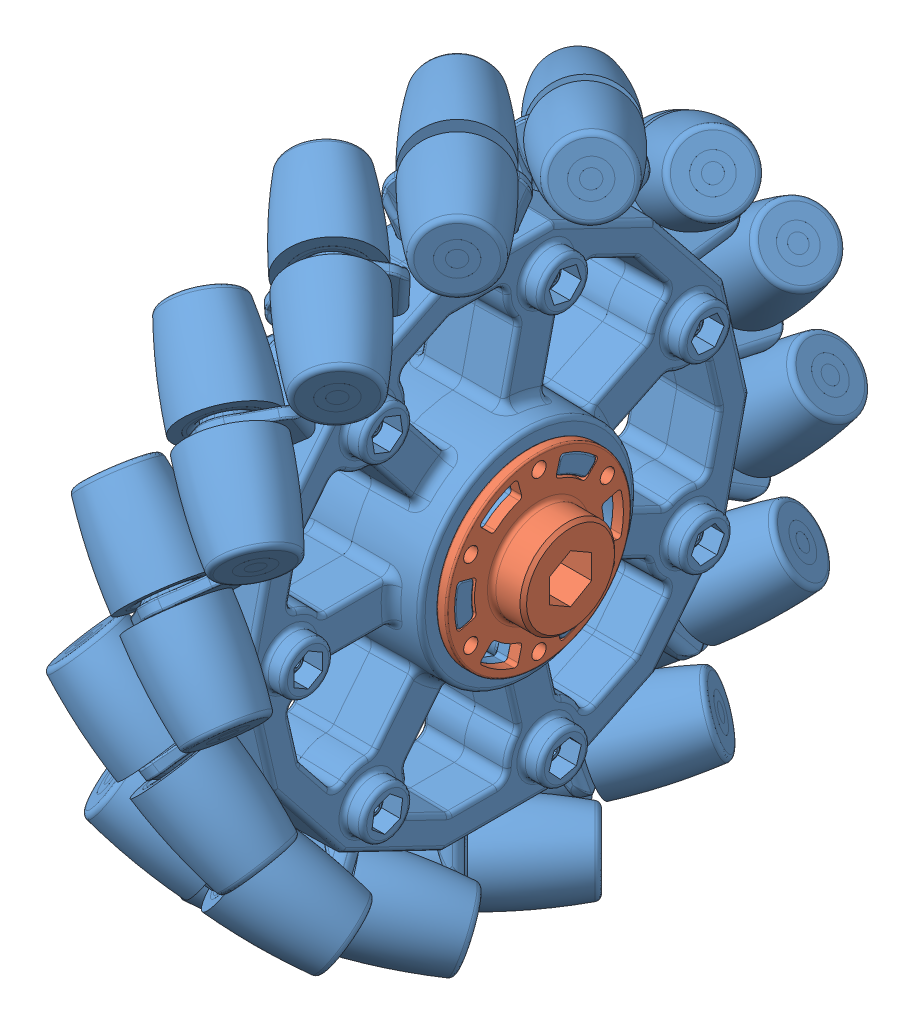
SolidWorks assembly 2018-202-A-Left, configuration Default. Lengths in mm.
Overall size (68.58 227.4 227.65).
3 component instances, 2 part files, 9 mates.
Components (placement in the parent):
- 2018-200-D017-Left-1: 2018-200-D017-Left [Default] x (0 -1 0) z (0 0 1) size (227.4 62.68 227.65)
- 2018-200-D005-1: 2018-200-D005 [Default] at (34.2942 0.0396 -0.0405) x (-1 0 0) z (0 -0.866025 -0.5) size (12.7 55.88 55.88)
- 2018-200-D005-2: 2018-200-D005 [Default] at (-34.2858 0.0396 -0.0405) size (12.7 55.88 55.88)
Mates (geometry in assembly coordinates):
- Coincident1: coincident: plane of 2018-200-D017-Left-1 through (0 0 0) normal (0 -1 0); plane of assembly
- Coincident2: coincident: plane of 2018-200-D017-Left-1 through (0 0 0) normal (0 0 1); plane of assembly
- Coincident3: coincident: plane of 2018-200-D017-Left-1 through (0 0 0) normal (1 0 0); plane of assembly
- Coincident4: coincident: plane of 2018-200-D017-Left-1 through (-21.5858 0.0396 -0.0405) normal (-1 0 0); plane of 2018-200-D005-2 through (-21.5858 31.5864 -0.0405) normal (1 0 0)
- Concentric1: concentric: cylinder of 2018-200-D017-Left-1 through (-18.4108 11.9459 -20.6627) axis (-1 0 0) radius 2.1526; cylinder of 2018-200-D005-2 through (-107.3791 11.9459 -20.6627) axis (1 0 0) radius 2.15
- Concentric2: concentric: cylinder of 2018-200-D017-Left-1 through (-18.4108 23.8521 -0.0405) axis (-1 0 0) radius 2.1526; cylinder of 2018-200-D005-2 through (-107.3791 23.8521 -0.0405) axis (1 0 0) radius 2.15
- Coincident5: coincident: plane of 2018-200-D017-Left-1 through (21.5942 0.0396 -0.0405) normal (1 0 0); plane of 2018-200-D005-1 through (21.5942 15.813 -27.3608) normal (-1 0 0)
- Concentric3: concentric: cylinder of 2018-200-D017-Left-1 through (18.4192 23.8521 -0.0405) axis (1 0 0) radius 2.1526; cylinder of 2018-200-D005-1 through (107.3876 23.8521 -0.0405) axis (-1 0 0) radius 2.15
- Concentric4: concentric: cylinder of 2018-200-D017-Left-1 through (18.4192 11.9459 -20.6627) axis (1 0 0) radius 2.1526; cylinder of 2018-200-D005-1 through (107.3876 11.9459 -20.6627) axis (-1 0 0) radius 2.15
